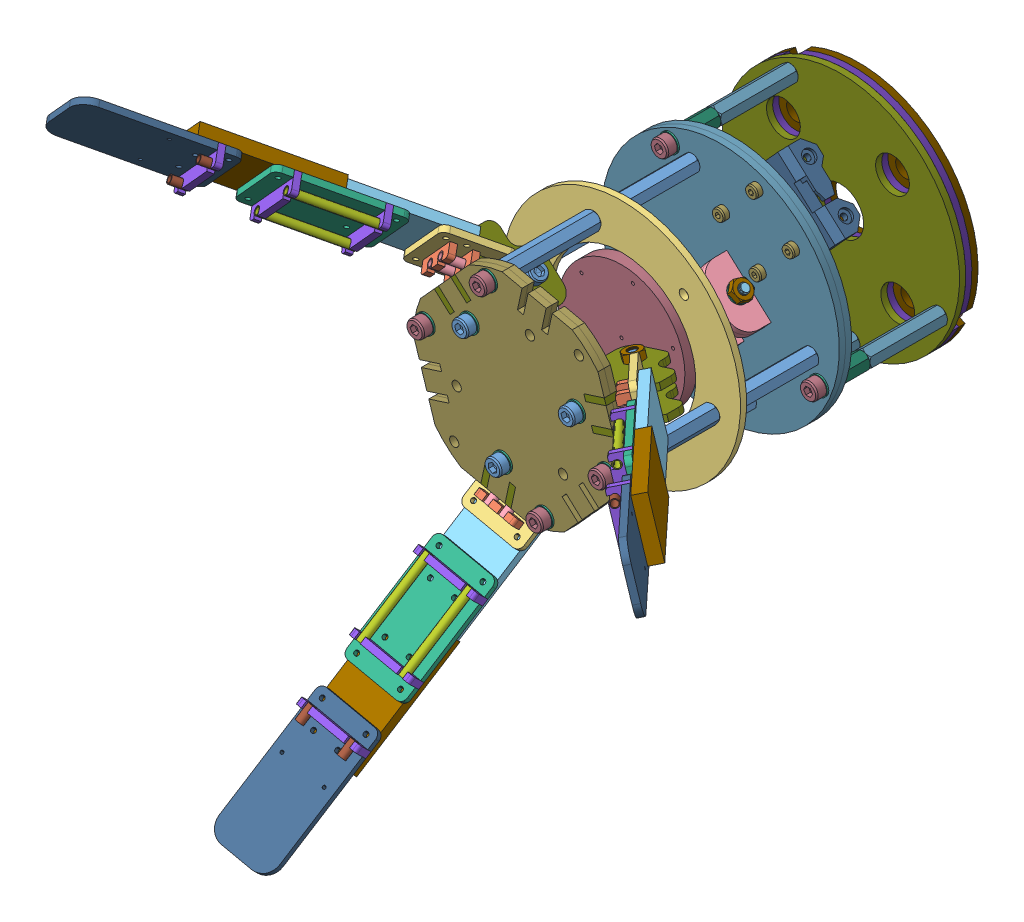
SolidWorks assembly RobotHand_AX12, configuration Default. Lengths in mm.
Overall size (222.55 244.19 178.63).
175 component instances, 36 part files, 41 mates.
Components (placement in the parent):
- RobotBaseAX12-1: RobotBaseAX12 [Default] at (-24.3366 65.8752 7.8296) size (108.77 108.77 76.29)
  - M3Spacer30-1: M3Spacer30 [Default] at (4.7282 -17.4075 3.4562) x (0.207823 -0.978166 0) z (-0.978166 -0.207823 0) size (6.28 30.59 5)
  - M3ThreadRod-1: M3ThreadRod [Default] at (4.7282 -17.4075 23.9562) x (0.200571 -0.979679 0) z (-0.979679 -0.200571 0) size (3.13 20.14 3.46)
  - MiddlePlate-1: MiddlePlate [Default] at (-4.4212 11.1633 35.4562) x (0.672277 0.7403 0) z (0 0 -1) size (77 77 2)
  - M3ThreadRod-2: M3ThreadRod [Default] at (-33.7389 17.525 23.9562) x (0.697343 -0.716737 0) z (-0.716737 -0.697343 0) size (3.13 20.14 3.46)
  - M3ThreadRod-3: M3ThreadRod [Default] at (-13.5706 39.734 23.9562) x (0.867995 0.496573 0) z (0.496573 -0.867995 0) size (3.13 20.14 3.46)
  - M3ThreadRod-4: M3ThreadRod [Default] at (24.8965 4.8015 23.9562) x (0.97301 -0.230763 0) z (-0.230763 -0.97301 0) size (3.13 20.14 3.46)
  - M3Spacer30-2: M3Spacer30 [Default] at (-13.5706 39.734 3.4562) x (0.207823 -0.978166 0) z (-0.978166 -0.207823 0) size (6.28 30.59 5)
  - M3Spacer30-3: M3Spacer30 [Default] at (-33.7389 17.525 3.4562) x (0.207823 -0.978166 0) z (-0.978166 -0.207823 0) size (6.28 30.59 5)
  - M3Spacer30-4: M3Spacer30 [Default] at (24.8965 4.8015 3.4562) x (0.207823 -0.978166 0) z (-0.978166 -0.207823 0) size (6.28 30.59 5)
  - M3Spacer30-5: M3Spacer30 [Default] at (-33.7389 17.525 35.4562) x (-0.803339 -0.595522 0) z (-0.595522 0.803339 0) size (6.28 30.59 5)
  - M3Spacer30-6: M3Spacer30 [Default] at (-13.5706 39.734 35.4562) x (-0.94995 -0.312401 0) z (-0.312401 0.94995 0) size (6.28 30.59 5)
  - M3Spacer30-7: M3Spacer30 [Default] at (24.8965 4.8015 35.4562) x (0.47318 -0.880966 0) z (-0.880966 -0.47318 0) size (6.28 30.59 5)
  - M3Spacer30-8: M3Spacer30 [Default] at (4.7282 -17.4075 35.4562) x (0.999987 -0.005046 0) z (-0.005046 -0.999987 0) size (6.28 30.59 5)
  - BearingBase-1: BearingBase [Default] at (-3.893 4.605 6.9562) x (0.7403 -0.672277 0) z (-0.672277 -0.7403 0) size (19.4 14 2)
  - BearingBase-2: BearingBase [Default] at (-5.2375 3.1244 6.9562) x (0.7403 -0.672277 0) z (-0.672277 -0.7403 0) size (19.4 14 2)
  - BearingBase-3: BearingBase [Default] at (3.5021 12.7483 6.9562) x (-0.7403 0.672277 0) z (0.672277 0.7403 0) size (19.4 14 2)
  - BearingBase-4: BearingBase [Default] at (2.1575 11.2677 6.9562) x (-0.7403 0.672277 0) z (0.672277 0.7403 0) size (19.4 14 2)
  - M3x20-1: M3x20 [Default] at (-6.5821 1.6438 6.9562) x (-0.399144 0.362469 -0.8422) z (-0.62348 0.566192 0.539166) size (5.5 23.77 5.5)
  - M3Washer-1: M3Washer [Default] at (-2.5484 6.0856 6.9562) x (-0.730674 0.663536 0.160736) z (-0.118993 0.108059 -0.986997) size (6 0.5 6)
  - PlasticSpacer-1: PlasticSpacer [Default] at (-2.5484 6.0856 6.9562) x (-0.284902 0.258724 -0.92298) z (-0.683282 0.620498 0.384847) size (6 2 6)
  - pulley-1: pulley [Default] at (0.4768 9.4169 6.9562) x (-0.418707 0.380234 0.824686) z (0.610515 -0.554418 0.565591) size (12 4 12)
  - M3Washer-2: M3Washer [Default] at (0.4768 9.4169 6.9562) x (0.735393 -0.667821 -0.114942) z (0.085091 -0.077273 0.993372) size (6 0.5 6)
  - PlasticSpacer-3: PlasticSpacer [Default] at (2.1575 11.2677 6.9562) x (0.683126 -0.620357 -0.385352) z (-0.285276 0.259063 -0.92277) size (6 2 6)
  - M3Nut-1: M3Nut [Default] at (4.8466 14.2289 6.9562) x (0.508771 -0.462022 0.726421) z (-0.53777 0.488356 0.68725) size (6.35 2.7 5.5)
  - M3Washer-3: M3Washer [Default] at (4.8466 14.2289 6.9562) x (0.506448 -0.459913 -0.729377) z (0.539957 -0.490343 0.684112) size (6 0.5 6)
  - AX12Base-1: AX12Base [Default] at (7.9887 31.5224 -0.5438) x (-0.7403 0.672277 0) z (-0.672277 -0.7403 0) size (25 9 38)
  - M2Nut-1: M2Nut [Default] at (7.4445 42.823 -4.5438) x (-0.340986 0.940068 0) z (0.940068 0.340986 0) size (4.58 1.66 4.98)
  - M2x8-1: M2x8 [Default] at (7.4445 42.823 3.4562) x (-0.96159 -0.27449 0) z (-0.27449 0.96159 0) size (3.8 10 3.8)
  - M2Nut-2: M2Nut [Default] at (8.5328 20.2218 -4.5438) x (0.64363 0.765337 0) z (0.765337 -0.64363 0) size (4.58 1.66 4.98)
  - M2Nut-3: M2Nut [Default] at (-3.312 30.9782 -4.5438) x (0.64363 0.765337 0) z (0.765337 -0.64363 0) size (4.58 1.66 4.98)
  - M2Nut-4: M2Nut [Default] at (19.2893 32.0666 -4.5438) x (0.64363 0.765337 0) z (0.765337 -0.64363 0) size (4.58 1.66 4.98)
  - M2x8-2: M2x8 [Default] at (8.5328 20.2218 3.4562) x (-0.634736 -0.772729 0) z (-0.772729 0.634736 0) size (3.8 10 3.8)
  - M2x8-3: M2x8 [Default] at (-3.312 30.9782 3.4562) x (0.897196 -0.441632 0) z (-0.441632 -0.897196 0) size (3.8 10 3.8)
  - M2x8-4: M2x8 [Default] at (19.2893 32.0666 3.4562) x (0.715995 -0.698105 0) z (-0.698105 -0.715995 0) size (3.8 10 3.8)
  - M3Washer-4: M3Washer [Default] at (4.7282 -17.4075 -0.5438) x (-0.207823 0.978166 0) z (-0.978166 -0.207823 0) size (6 0.5 6)
  - M3x10-1: M3x10 [Default] at (4.7282 -17.4075 -1.0438) x (0.990322 -0.138791 0) z (0.138791 0.990322 0) size (5.5 13.21 5.5)
  - M3x10-2: M3x10 [Default] at (-13.5706 39.734 -1.0438) x (-0.982342 -0.187094 0) z (0.187094 -0.982342 0) size (5.5 13.21 5.5)
  - M3x10-3: M3x10 [Default] at (-33.7389 17.525 -1.0438) x (-0.885366 0.464894 0) z (-0.464894 -0.885366 0) size (5.5 13.21 5.5)
  - M3x10-4: M3x10 [Default] at (24.8965 4.8015 -1.0438) x (-0.753911 0.656976 0) z (-0.656976 -0.753911 0) size (5.5 13.21 5.5)
  - M3Washer-5: M3Washer [Default] at (24.8965 4.8015 -0.5438) x (-0.207823 0.978166 0) z (-0.978166 -0.207823 0) size (6 0.5 6)
  - M3Washer-6: M3Washer [Default] at (-13.5706 39.734 -0.5438) x (-0.207823 0.978166 0) z (-0.978166 -0.207823 0) size (6 0.5 6)
  - M3Washer-7: M3Washer [Default] at (-33.7389 17.525 -0.5438) x (-0.207823 0.978166 0) z (-0.978166 -0.207823 0) size (6 0.5 6)
  - BottomPlateAX12-1: BottomPlateAX12 [Default] at (-4.4755 11.2126 -0.5438) x (0.672277 0.7403 0) z (0 0 1) size (77 77 2)
  - BottomPlateAX12-2: BottomPlateAX12 [Default] at (-4.4755 11.2126 1.4562) x (0.672277 0.7403 0) z (0 0 1) size (77 77 2)
  - PCBMount-1: PCBMount [Default] at (-18.642 5.8415 -7.5438) x (0.7403 -0.672277 0) z (0.672277 0.7403 0) size (31.5 14 2)
- FingersTopPlate-1: FingersTopPlate [Default] at (-347.7024 -151.4314 -84.4271) x (0.952359 0.30498 0) z (0.30498 -0.952359 0) size (173.84 105.63 200.74)
  - Finger_2ph-1: Finger_2ph [Default] at (386.8649 148.8938 -155.3548) x (0.5 0 0.866025) z (-0.866025 0 0.5) size (96.79 92.22 20)
    - FingerBase1-4: FingerBase1 [Default] at (-14.8634 -0.1306 24.1569) size (25.16 24.59 2)
    - FingerBase2-2: FingerBase2 [Default] at (3.2935 4.8192 29.1569) x (1 0 0) z (0 1 0) size (10 10 2)
    - FingerBase3-2: FingerBase3 [Default] at (3.2935 8.8192 29.1569) x (1 0 0) z (0 -1 0) size (10 6 2)
    - FingerBase1-5: FingerBase1 [Default] at (-14.8634 -0.1306 32.1569) size (25.16 24.59 2)
    - M3Nut-2: M3Nut [Default] at (1.3283 -5.6895 34.1569) x (0.826942 -0.562288 0) z (-0.562288 -0.826942 0) size (6.35 2.7 5.5)
    - M3Washer-5: M3Washer [Default] at (1.3283 -5.6895 26.6569) x (1 0 0) z (0 -1 0) size (6 0.5 6)
    - M3x12-2: M3x12 [Default] at (1.3283 -5.6895 21.6569) x (0 0 1) z (0.254118 -0.967173 0) size (15.11 5.3 5.3)
    - pulley-2: pulley [Default] at (1.3283 -5.6895 27.1569) x (1 0 0) z (0 -1 0) size (12 4 12)
    - M3Washer-6: M3Washer [Default] at (1.3283 -5.6895 26.1569) x (1 0 0) z (0 -1 0) size (6 0.5 6)
    - M3Washer-7: M3Washer [Default] at (1.3283 -5.6895 31.1569) x (1 0 0) z (0 -1 0) size (6 0.5 6)
    - M3Washer-8: M3Washer [Default] at (1.3283 -5.6895 31.6569) x (1 0 0) z (0 -1 0) size (6 0.5 6)
    - TubePlateMCP-5: TubePlateMCP [Default] at (-14.8634 7.405 24.6569) x (0 0 1) z (-0.707107 0.707107 0) size (13 6 2)
    - FingerMCP-4: FingerMCP [Default] at (-3.5497 -1.0803 19.1569) x (0 0 1) z (-0.707107 -0.707107 0) size (20 20 2)
    - TubePlateMCP-6: TubePlateMCP [Default] at (-10.6207 3.1623 24.6569) x (0 0 1) z (-0.707107 0.707107 0) size (13 6 2)
    - tubeMCP-5: tubeMCP [Default] at (-7.6155 6.1675 31.6569) x (0.694374 0.694374 0.188916) z (-0.707107 0.707107 0) size (2.5 2.5 8)
    - tubeMCP-6: tubeMCP [Default] at (-7.6155 6.1675 26.6569) x (0 0 1) z (-0.707107 0.707107 0) size (2.5 2.5 8)
    - Joint1-2: Joint1 [Default] at (-12.035 4.5765 20.1569) x (0 0 1) z (-0.707107 -0.707107 0) size (18 35 3)
    - FingerPIP-2: FingerPIP [Default] at (-24.7629 17.3045 39.1569) x (0 0 -1) z (0.707107 0.707107 0) size (20 36.1 2)
    - tubePIP-3: tubePIP [Default] at (-43.678 42.23 36.1569) x (0.652145 0.652145 -0.386542) z (0.707107 -0.707107 0) size (2.5 2.5 26)
    - TubePlate-5: TubePlate [Default] at (-46.7539 39.2955 39.1569) x (0 0 -1) z (0.707107 -0.707107 0) size (20 6 2)
    - TubePlate-6: TubePlate [Default] at (-29.7126 22.2542 39.1569) x (0 0 -1) z (0.707107 -0.707107 0) size (20 6 2)
    - tubePIP-4: tubePIP [Default] at (-43.678 42.23 22.1569) x (-0.184229 -0.184229 -0.965463) z (0.707107 -0.707107 0) size (2.5 2.5 26)
    - Joint2-2: Joint2 [Default] at (-39.6121 26.4969 38.1569) x (0 0 -1) z (0.707107 0.707107 0) size (18 39 4)
    - FingerDIP-2: FingerDIP [Default] at (-54.5321 49.9021 19.1569) x (0 0 1) z (-0.707107 -0.707107 0) size (20 43.2 2)
    - tubeDIP-3: tubeDIP [Default] at (-56.4766 55.0286 22.1569) x (0.662201 0.662201 -0.350685) z (-0.707107 0.707107 0) size (2.5 2.5 5)
    - tubeDIP-4: tubeDIP [Default] at (-56.4766 55.0286 36.1569) x (-0.686311 -0.686311 -0.240736) z (-0.707107 0.707107 0) size (2.5 2.5 5)
    - TubePlate-8: TubePlate [Default] at (-59.4818 52.0234 19.1569) x (0 0 1) z (-0.707107 0.707107 0) size (20 6 2)
  - TopPlate-1: TopPlate [Default] at (373.4285 159.713 -120.3137) x (0.866025 0 -0.5) z (0 -1 0) size (67 62.84 2)
  - Finger_2ph-2: Finger_2ph [Default] at (336.3638 148.8938 -114.4294) x (0.5 0 -0.866025) z (0.866025 0 0.5) size (96.79 92.22 20)
    - FingerBase1-4: FingerBase1 [Default] at (-14.8634 -0.1306 24.1569) size (25.16 24.59 2)
    - FingerBase2-2: FingerBase2 [Default] at (3.2935 4.8192 29.1569) x (1 0 0) z (0 1 0) size (10 10 2)
    - FingerBase3-2: FingerBase3 [Default] at (3.2935 8.8192 29.1569) x (1 0 0) z (0 -1 0) size (10 6 2)
    - FingerBase1-5: FingerBase1 [Default] at (-14.8634 -0.1306 32.1569) size (25.16 24.59 2)
    - M3Nut-2: M3Nut [Default] at (1.3283 -5.6895 34.1569) x (0.826942 -0.562288 0) z (-0.562288 -0.826942 0) size (6.35 2.7 5.5)
    - M3Washer-5: M3Washer [Default] at (1.3283 -5.6895 26.6569) x (1 0 0) z (0 -1 0) size (6 0.5 6)
    - M3x12-2: M3x12 [Default] at (1.3283 -5.6895 21.6569) x (0 0 1) z (0.254118 -0.967173 0) size (15.11 5.3 5.3)
    - pulley-2: pulley [Default] at (1.3283 -5.6895 27.1569) x (1 0 0) z (0 -1 0) size (12 4 12)
    - M3Washer-6: M3Washer [Default] at (1.3283 -5.6895 26.1569) x (1 0 0) z (0 -1 0) size (6 0.5 6)
    - M3Washer-7: M3Washer [Default] at (1.3283 -5.6895 31.1569) x (1 0 0) z (0 -1 0) size (6 0.5 6)
    - M3Washer-8: M3Washer [Default] at (1.3283 -5.6895 31.6569) x (1 0 0) z (0 -1 0) size (6 0.5 6)
    - TubePlateMCP-5: TubePlateMCP [Default] at (-14.8634 7.405 24.6569) x (0 0 1) z (-0.707107 0.707107 0) size (13 6 2)
    - FingerMCP-4: FingerMCP [Default] at (-3.5497 -1.0803 19.1569) x (0 0 1) z (-0.707107 -0.707107 0) size (20 20 2)
    - TubePlateMCP-6: TubePlateMCP [Default] at (-10.6207 3.1623 24.6569) x (0 0 1) z (-0.707107 0.707107 0) size (13 6 2)
    - tubeMCP-5: tubeMCP [Default] at (-7.6155 6.1675 31.6569) x (0.694374 0.694374 0.188916) z (-0.707107 0.707107 0) size (2.5 2.5 8)
    - tubeMCP-6: tubeMCP [Default] at (-7.6155 6.1675 26.6569) x (0 0 1) z (-0.707107 0.707107 0) size (2.5 2.5 8)
    - Joint1-2: Joint1 [Default] at (-12.035 4.5765 20.1569) x (0 0 1) z (-0.707107 -0.707107 0) size (18 35 3)
    - FingerPIP-2: FingerPIP [Default] at (-24.7629 17.3045 39.1569) x (0 0 -1) z (0.707107 0.707107 0) size (20 36.1 2)
    - tubePIP-3: tubePIP [Default] at (-43.678 42.23 36.1569) x (0.652145 0.652145 -0.386542) z (0.707107 -0.707107 0) size (2.5 2.5 26)
    - TubePlate-5: TubePlate [Default] at (-46.7539 39.2955 39.1569) x (0 0 -1) z (0.707107 -0.707107 0) size (20 6 2)
    - TubePlate-6: TubePlate [Default] at (-29.7126 22.2542 39.1569) x (0 0 -1) z (0.707107 -0.707107 0) size (20 6 2)
    - tubePIP-4: tubePIP [Default] at (-43.678 42.23 22.1569) x (-0.184229 -0.184229 -0.965463) z (0.707107 -0.707107 0) size (2.5 2.5 26)
    - Joint2-2: Joint2 [Default] at (-39.6121 26.4969 38.1569) x (0 0 -1) z (0.707107 0.707107 0) size (18 39 4)
    - FingerDIP-2: FingerDIP [Default] at (-54.5321 49.9021 19.1569) x (0 0 1) z (-0.707107 -0.707107 0) size (20 43.2 2)
    - tubeDIP-3: tubeDIP [Default] at (-56.4766 55.0286 22.1569) x (0.662201 0.662201 -0.350685) z (-0.707107 0.707107 0) size (2.5 2.5 5)
    - tubeDIP-4: tubeDIP [Default] at (-56.4766 55.0286 36.1569) x (-0.686311 -0.686311 -0.240736) z (-0.707107 0.707107 0) size (2.5 2.5 5)
    - TubePlate-8: TubePlate [Default] at (-59.4818 52.0234 19.1569) x (0 0 1) z (-0.707107 0.707107 0) size (20 6 2)
  - Finger_2ph-3: Finger_2ph [Default] at (397.0568 148.8938 -91.1568) x (-1 0 0) z (0 0 -1) size (96.79 92.22 20)
    - FingerBase1-4: FingerBase1 [Default] at (-14.8634 -0.1306 24.1569) size (25.16 24.59 2)
    - FingerBase2-2: FingerBase2 [Default] at (3.2935 4.8192 29.1569) x (1 0 0) z (0 1 0) size (10 10 2)
    - FingerBase3-2: FingerBase3 [Default] at (3.2935 8.8192 29.1569) x (1 0 0) z (0 -1 0) size (10 6 2)
    - FingerBase1-5: FingerBase1 [Default] at (-14.8634 -0.1306 32.1569) size (25.16 24.59 2)
    - M3Nut-2: M3Nut [Default] at (1.3283 -5.6895 34.1569) x (0.826942 -0.562288 0) z (-0.562288 -0.826942 0) size (6.35 2.7 5.5)
    - M3Washer-5: M3Washer [Default] at (1.3283 -5.6895 26.6569) x (1 0 0) z (0 -1 0) size (6 0.5 6)
    - M3x12-2: M3x12 [Default] at (1.3283 -5.6895 21.6569) x (0 0 1) z (0.254118 -0.967173 0) size (15.11 5.3 5.3)
    - pulley-2: pulley [Default] at (1.3283 -5.6895 27.1569) x (1 0 0) z (0 -1 0) size (12 4 12)
    - M3Washer-6: M3Washer [Default] at (1.3283 -5.6895 26.1569) x (1 0 0) z (0 -1 0) size (6 0.5 6)
    - M3Washer-7: M3Washer [Default] at (1.3283 -5.6895 31.1569) x (1 0 0) z (0 -1 0) size (6 0.5 6)
    - M3Washer-8: M3Washer [Default] at (1.3283 -5.6895 31.6569) x (1 0 0) z (0 -1 0) size (6 0.5 6)
    - TubePlateMCP-5: TubePlateMCP [Default] at (-14.8634 7.405 24.6569) x (0 0 1) z (-0.707107 0.707107 0) size (13 6 2)
    - FingerMCP-4: FingerMCP [Default] at (-3.5497 -1.0803 19.1569) x (0 0 1) z (-0.707107 -0.707107 0) size (20 20 2)
    - TubePlateMCP-6: TubePlateMCP [Default] at (-10.6207 3.1623 24.6569) x (0 0 1) z (-0.707107 0.707107 0) size (13 6 2)
    - tubeMCP-5: tubeMCP [Default] at (-7.6155 6.1675 31.6569) x (0.694374 0.694374 0.188916) z (-0.707107 0.707107 0) size (2.5 2.5 8)
    - tubeMCP-6: tubeMCP [Default] at (-7.6155 6.1675 26.6569) x (0 0 1) z (-0.707107 0.707107 0) size (2.5 2.5 8)
    - Joint1-2: Joint1 [Default] at (-12.035 4.5765 20.1569) x (0 0 1) z (-0.707107 -0.707107 0) size (18 35 3)
    - FingerPIP-2: FingerPIP [Default] at (-24.7629 17.3045 39.1569) x (0 0 -1) z (0.707107 0.707107 0) size (20 36.1 2)
    - tubePIP-3: tubePIP [Default] at (-43.678 42.23 36.1569) x (0.652145 0.652145 -0.386542) z (0.707107 -0.707107 0) size (2.5 2.5 26)
    - TubePlate-5: TubePlate [Default] at (-46.7539 39.2955 39.1569) x (0 0 -1) z (0.707107 -0.707107 0) size (20 6 2)
    - TubePlate-6: TubePlate [Default] at (-29.7126 22.2542 39.1569) x (0 0 -1) z (0.707107 -0.707107 0) size (20 6 2)
    - tubePIP-4: tubePIP [Default] at (-43.678 42.23 22.1569) x (-0.184229 -0.184229 -0.965463) z (0.707107 -0.707107 0) size (2.5 2.5 26)
    - Joint2-2: Joint2 [Default] at (-39.6121 26.4969 38.1569) x (0 0 -1) z (0.707107 0.707107 0) size (18 39 4)
    - FingerDIP-2: FingerDIP [Default] at (-54.5321 49.9021 19.1569) x (0 0 1) z (-0.707107 -0.707107 0) size (20 43.2 2)
    - tubeDIP-3: tubeDIP [Default] at (-56.4766 55.0286 22.1569) x (0.662201 0.662201 -0.350685) z (-0.707107 0.707107 0) size (2.5 2.5 5)
    - tubeDIP-4: tubeDIP [Default] at (-56.4766 55.0286 36.1569) x (-0.686311 -0.686311 -0.240736) z (-0.707107 0.707107 0) size (2.5 2.5 5)
    - TubePlate-8: TubePlate [Default] at (-59.4818 52.0234 19.1569) x (0 0 1) z (-0.707107 0.707107 0) size (20 6 2)
  - TopPlate-2: TopPlate [Default] at (373.4285 159.713 -120.3137) x (0.866025 0 0.5) z (0 1 0) size (67 62.84 2)
  - M3Washer-1: M3Washer [Default] at (393.7633 161.713 -120.3137) size (6 0.5 6)
  - M3Washer-2: M3Washer [Default] at (363.2611 161.713 -137.9241) size (6 0.5 6)
  - M3Washer-4: M3Washer [Default] at (363.2611 161.713 -102.7032) size (6 0.5 6)
  - M3x12-2: M3x12 [Default] at (363.2611 164.713 -137.9241) x (0 -1 0) z (0 0 1) size (15.11 5.3 5.3)
  - M3x12-3: M3x12 [Default] at (363.2611 164.713 -102.7032) x (0 -1 0) z (0.707518 0 0.706695) size (15.11 5.3 5.3)
  - M3x12-4: M3x12 [Default] at (393.7633 164.713 -120.3137) x (0 -1 0) z (0 0 1) size (15.11 5.3 5.3)
  - M3Nut-2: M3Nut [Default] at (363.2611 151.213 -137.9241) size (6.35 2.7 5.5)
  - M3Nut-3: M3Nut [Default] at (393.7633 151.213 -120.3137) x (-0.5 0 -0.866025) z (0.866025 0 -0.5) size (6.35 2.7 5.5)
  - M3Nut-4: M3Nut [Default] at (363.2611 151.213 -102.7032) size (6.35 2.7 5.5)
  - DifferentialDisk-1: DifferentialDisk [Default] at (373.4285 123.713 -120.3137) x (0.999997 0 -0.002461) z (0 1 0) size (41 41 4)
- FlangeAX12-1: FlangeAX12 [Default] at (-2127.4207 -38.5313 -1431.3397) x (-0.697386 -0.716696 0) z (0 0 1) size (79.61 79.61 41.15)
  - M3x10-1: M3x10 [Default] at (-1559.277 1455.5839 1401.6256) x (0.911881 0.410454 0) z (-0.410454 0.911881 0) size (5.5 13.21 5.5)
  - M3x10-2: M3x10 [Default] at (-1522.5204 1398.1902 1401.6256) x (-0.081495 -0.996674 0) z (0.996674 -0.081495 0) size (5.5 13.21 5.5)
  - M3x10-3: M3x10 [Default] at (-1557.0273 1390.3304 1401.6256) x (0.009393 0.999956 0) z (-0.999956 0.009393 0) size (5.5 13.21 5.5)
  - M3x10-4: M3x10 [Default] at (-1524.3108 1450.1194 1401.6256) x (-0.968317 0.249723 0) z (-0.249723 -0.968317 0) size (5.5 13.21 5.5)
  - M3Spacer25-1: M3Spacer25 [Default] at (-1522.5204 1398.1902 1403.6256) x (-0.353582 0.935404 0) z (0.935404 0.353582 0) size (6.28 25.53 5)
  - M3Spacer25-2: M3Spacer25 [Default] at (-1557.0273 1390.3304 1403.6256) x (-0.353582 0.935404 0) z (0.935404 0.353582 0) size (6.28 25.53 5)
  - M3Spacer25-3: M3Spacer25 [Default] at (-1559.277 1455.5839 1403.6256) x (-0.353582 0.935404 0) z (0.935404 0.353582 0) size (6.28 25.53 5)
  - M3Spacer25-4: M3Spacer25 [Default] at (-1524.3108 1450.1194 1403.6256) x (-0.353582 0.935404 0) z (0.935404 0.353582 0) size (6.28 25.53 5)
  - M3Spacer10-1: M3Spacer10 [Default] at (-1522.5204 1398.1902 1438.6256) x (-0.353582 0.935404 0) z (-0.935404 -0.353582 0) size (6.28 16.65 5)
  - M3Spacer10-2: M3Spacer10 [Default] at (-1557.0273 1390.3304 1438.6256) x (-0.353582 0.935404 0) z (-0.935404 -0.353582 0) size (6.28 16.65 5)
  - M3Spacer10-3: M3Spacer10 [Default] at (-1559.277 1455.5839 1438.6256) x (-0.353582 0.935404 0) z (-0.935404 -0.353582 0) size (6.28 16.65 5)
  - M3Spacer10-4: M3Spacer10 [Default] at (-1524.3108 1450.1194 1438.6256) x (-0.353582 0.935404 0) z (-0.935404 -0.353582 0) size (6.28 16.65 5)
  - flangeAX12_1-2: flangeAX12_1 [Default] at (-1546.402 1423.3623 1403.6256) x (-0.999406 -0.034457 0) z (0 0 -1) size (77 77 2)
  - flangeAX12_2-1: flangeAX12_2 [Default] at (-1546.402 1423.3623 1401.6256) x (-0.999406 -0.034457 0) z (0 0 -1) size (77 77 2)
  - flangeAX12_3-1: flangeAX12_3 [Default] at (-1546.402 1423.3623 1399.6256) x (-0.999406 -0.034457 0) z (0 0 -1) size (77 77 2)
- M3Washer-13: M3Washer [Default] at (0.56 70.6767 77.2859) x (1 0 0) z (0 -1 0) size (6 0.5 6)
- M3x10-9: M3x10 [Default] at (0.56 70.6767 77.7859) x (1 0 0) z (0 -1 0) size (5.5 13.21 5.5)
- M3x10-10: M3x10 [Default] at (-37.9071 105.6093 77.7859) x (1 0 0) z (0 -1 0) size (5.5 13.21 5.5)
- M3x10-11: M3x10 [Default] at (-19.6083 48.4677 77.7859) x (1 0 0) z (0 -1 0) size (5.5 13.21 5.5)
- M3x10-12: M3x10 [Default] at (-58.0754 83.4003 77.7859) x (1 0 0) z (0 -1 0) size (5.5 13.21 5.5)
- M3Washer-14: M3Washer [Default] at (-37.9071 105.6093 77.2859) x (0.692854 -0.721078 0) z (-0.721078 -0.692854 0) size (6 0.5 6)
- M3Washer-15: M3Washer [Default] at (-19.6083 48.4677 77.2859) x (1 0 0) z (0 -1 0) size (6 0.5 6)
- M3Washer-16: M3Washer [Default] at (-58.0754 83.4003 77.2859) x (1 0 0) z (0 -1 0) size (6 0.5 6)
- M3Washer-17: M3Washer [Default] at (-25.0933 42.6422 11.2859) x (1 0 0) z (0 -1 0) size (6 0.5 6)
- M3x10-14: M3x10 [Default] at (-25.0933 42.6422 11.7859) x (1 0 0) z (0 -1 0) size (5.5 13.21 5.5)
- M3Washer-18: M3Washer [Default] at (3.3142 63.7951 11.2859) x (1 0 0) z (0 -1 0) size (6 0.5 6)
- M3Washer-19: M3Washer [Default] at (-45.0216 107.6895 11.2859) x (1 0 0) z (0 -1 0) size (6 0.5 6)
- M3Washer-20: M3Washer [Default] at (-63.5592 77.5738 11.2859) x (1 0 0) z (0 -1 0) size (6 0.5 6)
- M3x10-15: M3x10 [Default] at (3.3142 63.7951 11.7859) x (1 0 0) z (0 -1 0) size (5.5 13.21 5.5)
- M3x10-16: M3x10 [Default] at (-45.0216 107.6895 11.7859) x (0.98819 -0.153236 0) z (-0.153236 -0.98819 0) size (5.5 13.21 5.5)
- M3x10-17: M3x10 [Default] at (-63.5592 77.5738 11.7859) x (1 0 0) z (0 -1 0) size (5.5 13.21 5.5)
Mates (geometry in assembly coordinates):
- Parallel1: parallel anti-aligned: plane of RobotBaseAX12-1/BottomPlateAX12-1 through (-28.7577 77.0385 7.2859) normal (0 0 -1); plane of FlangeAX12-1/flangeAX12_1-2 through (-28.8639 77.1349 -51.1494) normal (0 0 1)
- Parallel2: parallel aligned: plane of RobotBaseAX12-1/MiddlePlate-1 through (-28.7577 77.0385 43.2859) normal (0 0 1); plane of FingersTopPlate-1/TopPlate-1 through (-28.7577 77.0385 75.2859) normal (0 0 1)
- Concentric7: concentric aligned: circle of M3x10-10; circle of M3Washer-14
- Coincident4: coincident anti-aligned: plane of M3x10-10 through (-37.9071 105.6093 77.7859) normal (0 0 -1); plane of M3Washer-14 through (-37.9071 105.6093 77.7859) normal (0 0 1)
- Concentric8: concentric aligned: circle of M3x10-11; circle of M3Washer-15
- Coincident5: coincident anti-aligned: plane of M3x10-11 through (-19.6083 48.4677 77.7859) normal (0 0 -1); plane of M3Washer-15 through (-19.6083 48.4677 77.7859) normal (0 0 1)
- Concentric9: concentric aligned: circle of M3Washer-13; circle of M3x10-9
- Coincident6: coincident anti-aligned: plane of M3Washer-13 through (0.56 70.6767 77.7859) normal (0 0 1); plane of M3x10-9 through (0.56 70.6767 77.7859) normal (0 0 -1)
- Concentric10: concentric aligned: circle of M3x10-12; circle of M3Washer-16
- Coincident7: coincident anti-aligned: plane of M3x10-12 through (-58.0754 83.4003 77.7859) normal (0 0 -1); plane of M3Washer-16 through (-58.0754 83.4003 77.7859) normal (0 0 1)
- Concentric15: concentric aligned: circle of M3Washer-17; circle of M3x10-14
- Coincident12: coincident anti-aligned: plane of M3Washer-17 through (-25.0933 42.6422 11.7859) normal (0 0 1); plane of M3x10-14 through (-25.0933 42.6422 11.7859) normal (0 0 -1)
- Concentric16: concentric aligned: circle of RobotBaseAX12-1/BottomPlateAX12-2; circle of M3Washer-17
- Coincident13: coincident anti-aligned: plane of RobotBaseAX12-1/BottomPlateAX12-2 through (-28.7577 77.0385 11.2859) normal (0 0 1); plane of M3Washer-17 through (-25.0933 42.6422 11.2859) normal (0 0 -1)
- Concentric17: concentric aligned: circle of M3Washer-18; circle of M3x10-15
- Coincident14: coincident anti-aligned: plane of M3Washer-18 through (3.3142 63.7951 11.7859) normal (0 0 1); plane of M3x10-15 through (3.3142 63.7951 11.7859) normal (0 0 -1)
- Concentric18: concentric aligned: circle of RobotBaseAX12-1/BottomPlateAX12-2; circle of M3Washer-18
- Coincident15: coincident anti-aligned: plane of RobotBaseAX12-1/BottomPlateAX12-2 through (-28.7577 77.0385 11.2859) normal (0 0 1); plane of M3Washer-18 through (3.3142 63.7951 11.2859) normal (0 0 -1)
- Concentric19: concentric aligned: circle of M3Washer-19; circle of M3x10-16
- Coincident16: coincident anti-aligned: plane of M3Washer-19 through (-45.0216 107.6895 11.7859) normal (0 0 1); plane of M3x10-16 through (-45.0216 107.6895 11.7859) normal (0 0 -1)
- Concentric20: concentric aligned: circle of RobotBaseAX12-1/BottomPlateAX12-2; circle of M3Washer-19
- Coincident17: coincident anti-aligned: plane of RobotBaseAX12-1/BottomPlateAX12-2 through (-28.7577 77.0385 11.2859) normal (0 0 1); plane of M3Washer-19 through (-45.0216 107.6895 11.2859) normal (0 0 -1)
- Concentric21: concentric aligned: circle of M3Washer-20; circle of M3x10-17
- Coincident18: coincident anti-aligned: plane of M3Washer-20 through (-63.5592 77.5738 11.7859) normal (0 0 1); plane of M3x10-17 through (-63.5592 77.5738 11.7859) normal (0 0 -1)
- Concentric22: concentric aligned: circle of RobotBaseAX12-1/BottomPlateAX12-2; circle of M3Washer-20
- Coincident19: coincident anti-aligned: plane of RobotBaseAX12-1/BottomPlateAX12-2 through (-28.7577 77.0385 11.2859) normal (0 0 1); plane of M3Washer-20 through (-63.5592 77.5738 11.2859) normal (0 0 -1)
- Concentric23: concentric anti-aligned: circle of RobotBaseAX12-1/MiddlePlate-1; circle of FingersTopPlate-1/TopPlate-2
- Concentric24: concentric anti-aligned: circle of RobotBaseAX12-1/MiddlePlate-1; circle of FingersTopPlate-1/TopPlate-2
- Concentric25: concentric anti-aligned: circle of RobotBaseAX12-1/MiddlePlate-1; circle of FingersTopPlate-1/TopPlate-2
- Coincident22: coincident anti-aligned: plane of RobotBaseAX12-1/M3Spacer30-5 through (-58.0754 83.4003 73.2859) normal (0 0 1); plane of FingersTopPlate-1/TopPlate-1 through (-28.7577 77.0385 73.2859) normal (0 0 -1)
- Concentric26: concentric aligned: circle of FingersTopPlate-1/TopPlate-2; circle of M3Washer-14
- Coincident23: coincident anti-aligned: plane of FingersTopPlate-1/TopPlate-2 through (-28.7577 77.0385 77.2859) normal (0 0 1); plane of M3Washer-14 through (-37.9071 105.6093 77.2859) normal (0 0 -1)
- Concentric27: concentric aligned: circle of FingersTopPlate-1/TopPlate-2; circle of M3Washer-13
- Coincident24: coincident anti-aligned: plane of FingersTopPlate-1/TopPlate-2 through (-28.7577 77.0385 77.2859) normal (0 0 1); plane of M3Washer-13 through (0.56 70.6767 77.2859) normal (0 0 -1)
- Concentric28: concentric aligned: circle of FingersTopPlate-1/TopPlate-2; circle of M3Washer-15
- Coincident25: coincident anti-aligned: plane of FingersTopPlate-1/TopPlate-2 through (-28.7577 77.0385 77.2859) normal (0 0 1); plane of M3Washer-15 through (-19.6083 48.4677 77.2859) normal (0 0 -1)
- Concentric29: concentric aligned: circle of FingersTopPlate-1/TopPlate-2; circle of M3Washer-16
- Coincident26: coincident anti-aligned: plane of FingersTopPlate-1/TopPlate-2 through (-28.7577 77.0385 77.2859) normal (0 0 1); plane of M3Washer-16 through (-58.0754 83.4003 77.2859) normal (0 0 -1)
- Concentric30: concentric anti-aligned: circle of FlangeAX12-1/M3x10-4; circle of M3x10-14
- Concentric33: concentric anti-aligned: circle of FlangeAX12-1/M3x10-2; circle of M3x10-17
- Coincident27: coincident anti-aligned: plane of RobotBaseAX12-1/BottomPlateAX12-1 through (-28.7577 77.0385 7.2859) normal (0 0 -1); plane of FlangeAX12-1/M3Spacer10-1 through (-63.5592 77.5738 7.2859) normal (0 0 1)
